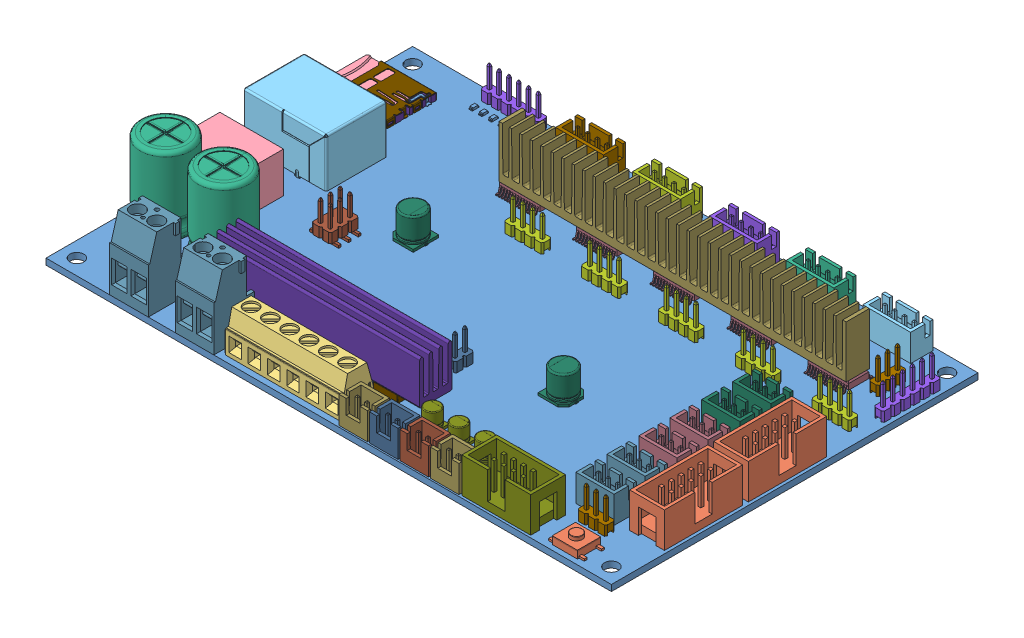
SolidWorks assembly MKS SBase V1.3, configuration Default. Lengths in mm.
Overall size (148.75 24.1 95).
76 component instances, 39 part files, 151 mates.
Components (placement in the parent):
- MKS SBase PCB-1: MKS SBase PCB [Default] at origin size (146.5 1.6 95)
- 10 pin male socket -2: 10 pin male socket  [Default] at (92.5901 0 -6.7406) x (0 0 -1) z (1 0 0) size (20.25 12.5 9)
- 10 pin male socket -3: 10 pin male socket  [Default] at (92.5901 0 -28.4906) x (0 0 -1) z (1 0 0) size (20.25 12.5 9)
- 6 pin terminal block-1: 6 pin terminal block [Default] at (-13.25 0 37.7021) size (30.6 13.8 8.3)
- USB socket-1: USB socket [Default] at (-15.2875 4.6912 16.0684) size (16.5 14.22 14.86)
- JST XH 4 Purple-1: JST XH 4 Purple [Default] at (56.25 0 -43.725) x (-1 0 0) z (0 0 -1) size (12.4 10.45 5.75)
- JST XH 4 Black-1: JST XH 4 Black [Default] at (36.35 0 -43.725) x (-1 0 0) z (0 0 -1) size (12.4 10.45 5.75)
- JST XH 4 Blue-1: JST XH 4 Blue [Default] at (-3.45 0 -43.725) x (-1 0 0) z (0 0 -1) size (12.4 10.45 5.75)
- JST XH 4 Green-1: JST XH 4 Green [Default] at (16.45 0 -43.725) x (-1 0 0) z (0 0 -1) size (12.4 10.45 5.75)
- JST XH 4 Red-1: JST XH 4 Red [Default] at (-23.35 0 -43.725) x (-1 0 0) z (0 0 -1) size (12.4 10.45 5.75)
- JST XH 2 Black-1: JST XH 2 Black [Default] at (13.85 0 44.225) size (7.4 10.45 5.75)
- JST XH 2 Purple-1: JST XH 2 Purple [Default] at (21.75 0 44.225) size (7.4 10.45 5.75)
- JST XH 2 White-1: JST XH 2 White [Default] at (5.95 0 44.225) size (7.4 10.45 5.75)
- JST XH 3 Blue-1: JST XH 3 Blue [Default] at (55.4 0 14.725) x (-1 0 0) z (0 0 -1) size (9.9 10.45 5.75)
- JST XH 3 Green-1: JST XH 3 Green [Default] at (55.4 0 31.025) x (-1 0 0) z (0 0 -1) size (9.9 10.45 5.75)
- JST XH 3 Red-1: JST XH 3 Red [Default] at (55.4 0 -1.575) x (-1 0 0) z (0 0 -1) size (9.9 10.45 5.75)
- JST XH 2 White-2: JST XH 2 White [Default] at (29.65 0 44.225) size (7.4 10.45 5.75)
- 8 pin male socket -1: 8 pin male socket  [Default] at (71.2406 0 66.9901) size (17.85 12.5 9)
- JST XH 3 Blue-2: JST XH 3 Blue [Default] at (55.4 0 6.675) x (-1 0 0) z (0 0 -1) size (9.9 10.45 5.75)
- JST XH 3 Green-2: JST XH 3 Green [Default] at (55.4 0 22.975) x (-1 0 0) z (0 0 -1) size (9.9 10.45 5.75)
- JST XH 3 Red-2: JST XH 3 Red [Default] at (55.4 0 -9.625) x (-1 0 0) z (0 0 -1) size (9.9 10.45 5.75)
- microSD_Connector-1: microSD_Connector [Default] at (-65.65 0 -31.475) x (0 0 -1) z (1 0 0) size (14.1 2.14 15.45)
  - microSD_Body-1: microSD_Body [Default] at origin size (14.1 1.85 15.2)
  - microSD_Cover-1: microSD_Cover [Default] at (0 1.7 0) x (1 0 0) z (0 0 -1) size (13.95 1.9 15.2)
  - microSD_Card_Detect-1: microSD_Card_Detect [Default] at (4.99 -0.05 7.4) size (4.45 1.9 2.05)
  - microSD_Spring-2: microSD_Spring [Default] at (-3.85 1.125 6.9) x (-0.521999 -0.852946 0) z (0.852946 -0.521999 0) size (1.41 10.35 1.43)
  - microSD_Pin-1: microSD_Pin [11.15] at (5.725 -0.05 -2) x (0 0 1) z (-1 0 0) size (7.35 1.15 0.6)
  - microSD_Pin-2: microSD_Pin [11.15] at (4.625 -0.05 -2) x (0 0 1) z (-1 0 0) size (7.35 1.15 0.6)
  - microSD_Pin-3: microSD_Pin [11.35] at (3.525 -0.05 -2) x (0 0 1) z (-1 0 0) size (7.35 1.15 0.6)
  - microSD_Pin-4: microSD_Pin [11.15] at (2.425 -0.05 -2) x (0 0 1) z (-1 0 0) size (7.35 1.15 0.6)
  - microSD_Pin-5: microSD_Pin [11.35] at (1.325 -0.05 -2) x (0 0 1) z (-1 0 0) size (7.35 1.15 0.6)
  - microSD_Pin-6: microSD_Pin [11.15] at (0.225 -0.05 -2) x (0 0 1) z (-1 0 0) size (7.35 1.15 0.6)
  - microSD_Pin-7: microSD_Pin [10.75] at (-0.875 -0.05 -2) x (0 0 1) z (-1 0 0) size (7.25 1.15 0.6)
  - microSD_Pin-8: microSD_Pin [11.15] at (-1.975 -0.05 -2) x (0 0 1) z (-1 0 0) size (7.35 1.15 0.6)
- Micro SD Card-1: Micro SD Card [Default] at (-68 1.05 -33.35) x (0 0 1) z (-1 0 0) size (11 0.83 15)
- RJ45_10P_TJ3009-1: RJ45_10P_TJ3009 [Default] at (-61.925 0.35 -11.1) x (0 0 1) z (-1 0 0) size (16 15.87 21.5)
- Condensator-1: Condensator [Default] at (-65.75 0.15 24) x (-1 0 0) z (0 0 -1) size (13.15 23 13.15)
- Condensator-2: Condensator [Default] at (-50.75 0.15 24) x (-1 0 0) z (0 0 -1) size (13.15 23 13.15)
- 2.54 pins 4 x 1-1: 2.54 pins 4 x 1 [Default] at (-14.68 0 -18.75) x (1 0 0) z (0 0 -1) size (10.06 11 2.5)
- 2.54 pins 4 x 1-5: 2.54 pins 4 x 1 [Default] at (25.12 0 -18.75) x (1 0 0) z (0 0 -1) size (10.06 11 2.5)
- 2.54 pins 4 x 1-6: 2.54 pins 4 x 1 [Default] at (45.02 0 -18.75) x (1 0 0) z (0 0 -1) size (10.06 11 2.5)
- 2.54 pins 4 x 1-7: 2.54 pins 4 x 1 [Default] at (64.92 0 -18.75) x (1 0 0) z (0 0 -1) size (10.06 11 2.5)
- 2.54 pins 4 x 1-8: 2.54 pins 4 x 1 [Default] at (5.22 0 -18.75) x (1 0 0) z (0 0 -1) size (10.06 11 2.5)
- 2.54 pins 6 x 1-1: 2.54 pins 6 x 1 [Default] at (71 0 -37.8175) x (0 0 1) z (-1 0 0) size (15.09 11 2.5)
- 2.54 pins 6 x 1-3: 2.54 pins 6 x 1 [Default] at (-51.2675 0 -45.4) size (15.09 11 2.5)
- 2.54 pins 3 x 1-3: 2.54 pins 3 x 1 [Default] at (55.6125 0 36.35) size (7.47 11 2.5)
- 2.54 pins 3 x 1-4: 2.54 pins 3 x 1 [Default] at (64.6 0 -30.2125) x (0 0 -1) z (1 0 0) size (7.47 11 2.5)
- 2.54 pins 2 x 1-1: 2.54 pins 2 x 1 [Default] at (4.5 0 19.2475) x (0 0 -1) z (1 0 0) size (4.93 11 2.5)
- 2.54 pins 3 x 2-3: 2.54 pins 3 x 2 [Default] at (-42.5 0.64 7.0875) x (0 0 -1) z (1 0 0) size (7.47 8.64 7.5)
- Stepper driver heatsink-1: Stepper driver heatsink [Default] at (15.75 9.25 -28.85) x (0 0 -1) z (1 0 0) size (6 13.5 90)
- Stepper driver-1: Stepper driver [Default] at (55.75 1.35 -28.85) x (0 0 -1) z (1 0 0) size (8 2.5 10.5)
- Stepper driver-2: Stepper driver [Default] at (35.75 1.35 -28.85) x (0 0 -1) z (1 0 0) size (8 2.5 10.5)
- Stepper driver-3: Stepper driver [Default] at (15.75 1.35 -28.85) x (0 0 -1) z (1 0 0) size (8 2.5 10.5)
- Stepper driver-4: Stepper driver [Default] at (-4.25 1.35 -28.85) x (0 0 -1) z (1 0 0) size (8 2.5 10.5)
- Stepper driver-5: Stepper driver [Default] at (-24.25 1.35 -28.85) x (0 0 -1) z (1 0 0) size (8 2.5 10.5)
- Power terminal block-1: Power terminal block [Default] at (-51.75 0 42.25) x (-1 0 0) z (0 0 -1) size (10.55 20.8 10.5)
- Power terminal block-2: Power terminal block [Default] at (-34.75 0 42.25) x (-1 0 0) z (0 0 -1) size (10.55 20.8 10.5)
- Elco100_35-5: Elco100_35 [Default] at (-30.25 0.64 -4.65) x (0 0 1) z (-1 0 0) size (6.6 6.95 7)
- Elco100_35-6: Elco100_35 [Default] at (24.65 0.64 11.3) x (0 0 -1) z (1 0 0) size (6.6 6.95 7)
- Elco100_35-7: Elco100_35 [Default] at (-32.05 0.64 -36) x (0 0 -1) z (1 0 0) size (6.6 6.95 7)
- Elco100_35-8: Elco100_35 [Default] at (-12.05 0.64 -36) x (0 0 -1) z (1 0 0) size (6.6 6.95 7)
- Elco100_35-9: Elco100_35 [Default] at (7.95 0.64 -36) x (0 0 -1) z (1 0 0) size (6.6 6.95 7)
- Elco100_35-10: Elco100_35 [Default] at (27.95 0.64 -36) x (0 0 -1) z (1 0 0) size (6.6 6.95 7)
- Elco100_35-11: Elco100_35 [Default] at (47.95 0.64 -36) x (0 0 -1) z (1 0 0) size (6.6 6.95 7)
- Elco10_35-1: Elco10_35 [Default] at (35.2 0.64 35.25) size (4.3 4.65 4.6)
- Elco10_35-2: Elco10_35 [Default] at (28.35 0.64 35.25) size (4.3 4.65 4.6)
- Elco10_35-3: Elco10_35 [Default] at (21.5 0.64 35.25) size (4.3 4.65 4.6)
- Elco10_35-4: Elco10_35 [Default] at (14.65 0.64 35.25) size (4.3 4.65 4.6)
- Power FAT heatsink-1: Power FAT heatsink [Default] at (-16.55 2 30.7) size (55 11.25 8.49)
- Power FAT-1: Power FAT [Default] at (-34.925 0 30.7) x (-1 0 0) z (0 0 -1) size (6.35 2 11)
- Power FAT-2: Power FAT [Default] at (-22.675 0 30.7) x (-1 0 0) z (0 0 -1) size (6.35 2 11)
- Power FAT-3: Power FAT [Default] at (-10.425 0 30.7) x (-1 0 0) z (0 0 -1) size (6.35 2 11)
- Power FAT-4: Power FAT [Default] at (1.825 0 30.7) x (-1 0 0) z (0 0 -1) size (6.35 2 11)
- Series of LEDs-1: Series of LEDs [Default] at (-46.425 0 -41.575) size (10.85 0.6 1.75)
- Reset button-1: Reset button [Default] at (59.9 0 43.2) size (9.25 2.95 6.02)
- 4 LEDs power outputs-1: 4 LEDs power outputs [Default] at (-12.2 0 25.075) size (37.6 0.6 1.75)
Mates (geometry in assembly coordinates):
- Coincident3: coincident aligned: plane of MKS SBase PCB-1 through (0 0 0) normal (1 0 0); plane of assembly through (0 0 0) normal (1 0 0)
- Coincident8: coincident aligned: plane of 10 pin male socket -2 through (72.5 9.1 33) normal (1 0 0); plane of 10 pin male socket -3 through (72.5 9.1 11.25) normal (1 0 0)
- Distance3: distance = 14.5 mm aligned: plane of 10 pin male socket -2 through (63.5 9.1 33) normal (0 0 1); plane of MKS SBase PCB-1 through (-73.25 -1.6 47.5) normal (0 0 1)
- Distance4: distance = 42 mm anti-aligned: plane of 10 pin male socket -2 through (63.5 9.1 33) normal (0 0 1); plane of 10 pin male socket -3 through (63.5 9.1 -9) normal (0 0 -1)
- Distance5: distance = 0.75 mm aligned: plane of 10 pin male socket -2 through (72.5 9.1 33) normal (1 0 0); plane of MKS SBase PCB-1 through (73.25 -1.6 -47.5) normal (1 0 0)
- Coincident15: coincident anti-aligned: plane of MKS SBase PCB-1 through (0 0 0) normal (0 1 0); plane of 6 pin terminal block-1 through (1.75 0 46) normal (0 -1 0)
- Distance6: distance = 71.5 mm aligned: plane of 6 pin terminal block-1 through (1.75 7.1842 38.5787) normal (1 0 0); plane of MKS SBase PCB-1 through (73.25 -1.6 -47.5) normal (1 0 0)
- Distance7: distance = 1.5 mm aligned: plane of 6 pin terminal block-1 through (1.75 5.6981 46) normal (0 0 1); plane of MKS SBase PCB-1 through (-73.25 -1.6 47.5) normal (0 0 1)
- Coincident18: coincident anti-aligned: plane of MKS SBase PCB-1 through (0 0 0) normal (0 1 0); plane of USB socket-1 through (-72.95 0 2.75) normal (0 -1 0)
- Distance8: distance = 44.75 mm anti-aligned: plane of USB socket-1 through (-72.95 10.5 2.75) normal (0 0 -1); plane of MKS SBase PCB-1 through (-73.25 -1.6 47.5) normal (0 0 1)
- Distance9: distance = 0.3 mm aligned: plane of USB socket-1 through (-72.95 0 2.75) normal (-1 0 0); plane of MKS SBase PCB-1 through (-73.25 -1.6 -47.5) normal (-1 0 0)
- Coincident21: coincident aligned: plane of JST XH 4 Black-1 through (36.35 0 -43.725) normal (0 -1 0); plane of JST XH 4 Blue-1 through (-3.45 0 -43.725) normal (0 -1 0)
- Coincident22: coincident aligned: plane of JST XH 4 Purple-1 through (56.25 0 -43.725) normal (0 -1 0); plane of JST XH 4 Blue-1 through (-3.45 0 -43.725) normal (0 -1 0)
- Coincident26: coincident aligned: plane of JST XH 4 Black-1 through (42.55 7 -40.85) normal (0 0 1); plane of JST XH 4 Blue-1 through (2.75 7 -40.85) normal (0 0 1)
- Coincident27: coincident aligned: plane of JST XH 4 Blue-1 through (2.75 7 -40.85) normal (0 0 1); plane of JST XH 4 Green-1 through (22.65 7 -40.85) normal (0 0 1)
- Distance15: distance = 0.9 mm aligned: plane of MKS SBase PCB-1 through (-73.25 -1.6 -47.5) normal (0 0 -1); plane of JST XH 4 Red-1 through (-17.15 7 -46.6) normal (0 0 -1)
- Coincident37: coincident anti-aligned: plane of MKS SBase PCB-1 through (0 0 0) normal (0 1 0); plane of JST XH 4 Red-1 through (-23.35 0 -43.725) normal (0 -1 0)
- Distance16: distance = 43.7 mm aligned: plane of MKS SBase PCB-1 through (-73.25 -1.6 -47.5) normal (-1 0 0); plane of JST XH 4 Red-1 through (-29.55 7 -40.85) normal (-1 0 0)
- Coincident39: coincident aligned: plane of JST XH 4 Blue-1 through (2.75 7 -40.85) normal (0 0 1); plane of JST XH 4 Red-1 through (-17.15 7 -40.85) normal (0 0 1)
- Coincident40: coincident anti-aligned: plane of MKS SBase PCB-1 through (0 0 0) normal (0 1 0); plane of JST XH 4 Blue-1 through (-3.45 0 -43.725) normal (0 -1 0)
- Distance17: distance = 7.5 mm anti-aligned: plane of JST XH 4 Blue-1 through (-9.65 7 -40.85) normal (-1 0 0); plane of JST XH 4 Red-1 through (-17.15 7 -40.85) normal (1 0 0)
- Distance18: distance = 7.5 mm anti-aligned: plane of JST XH 4 Green-1 through (10.25 7 -40.85) normal (-1 0 0); plane of JST XH 4 Blue-1 through (2.75 7 -40.85) normal (1 0 0)
- Distance19: distance = 7.5 mm anti-aligned: plane of JST XH 4 Black-1 through (30.15 7 -40.85) normal (-1 0 0); plane of JST XH 4 Green-1 through (22.65 7 -40.85) normal (1 0 0)
- Coincident44: coincident aligned: plane of JST XH 4 Purple-1 through (62.45 7 -46.6) normal (0 0 -1); plane of JST XH 4 Black-1 through (42.55 7 -46.6) normal (0 0 -1)
- Distance20: distance = 7.5 mm anti-aligned: plane of JST XH 4 Purple-1 through (50.05 7 -40.85) normal (-1 0 0); plane of JST XH 4 Black-1 through (42.55 7 -40.85) normal (1 0 0)
- Coincident47: coincident aligned: plane of JST XH 2 Purple-1 through (18.05 7 47.1) normal (0 0 1); plane of JST XH 2 White-2 through (25.95 7 47.1) normal (0 0 1)
- Coincident48: coincident aligned: plane of JST XH 2 Black-1 through (10.15 7 47.1) normal (0 0 1); plane of JST XH 2 Purple-1 through (18.05 7 47.1) normal (0 0 1)
- Coincident49: coincident aligned: plane of JST XH 2 Black-1 through (10.15 7 47.1) normal (0 0 1); plane of JST XH 2 White-1 through (2.25 7 47.1) normal (0 0 1)
- Coincident50: coincident aligned: plane of JST XH 2 Black-1 through (13.85 0 44.225) normal (0 -1 0); plane of JST XH 2 White-2 through (29.65 0 44.225) normal (0 -1 0)
- Coincident51: coincident aligned: plane of JST XH 2 Purple-1 through (21.75 0 44.225) normal (0 -1 0); plane of JST XH 2 White-2 through (29.65 0 44.225) normal (0 -1 0)
- Coincident52: coincident aligned: plane of JST XH 2 Purple-1 through (21.75 0 44.225) normal (0 -1 0); plane of JST XH 2 White-1 through (5.95 0 44.225) normal (0 -1 0)
- Coincident53: coincident anti-aligned: plane of MKS SBase PCB-1 through (0 0 0) normal (0 1 0); plane of JST XH 2 Black-1 through (13.85 0 44.225) normal (0 -1 0)
- Coincident54: coincident anti-aligned: plane of MKS SBase PCB-1 through (0 0 0) normal (0 1 0); plane of 8 pin male socket -1 through (71.2406 0 66.9901) normal (0 -1 0)
- Distance21: distance = 21.5 mm aligned: plane of 8 pin male socket -1 through (51.75 9.1 37.9) normal (1 0 0); plane of MKS SBase PCB-1 through (73.25 -1.6 -47.5) normal (1 0 0)
- Distance22: distance = 0.6 mm aligned: plane of 8 pin male socket -1 through (33.9 9.1 46.9) normal (0 0 1); plane of MKS SBase PCB-1 through (-73.25 -1.6 47.5) normal (0 0 1)
- Distance23: distance = 0.4 mm aligned: plane of JST XH 2 White-1 through (2.25 7 47.1) normal (0 0 1); plane of MKS SBase PCB-1 through (-73.25 -1.6 47.5) normal (0 0 1)
- Distance24: distance = 0.5 mm anti-aligned: plane of 6 pin terminal block-1 through (1.75 7.1842 38.5787) normal (1 0 0); plane of JST XH 2 White-1 through (2.25 7 41.35) normal (-1 0 0)
- Distance25: distance = 0.5 mm anti-aligned: plane of JST XH 2 White-1 through (9.65 7 41.35) normal (1 0 0); plane of JST XH 2 Black-1 through (10.15 7 41.35) normal (-1 0 0)
- Distance26: distance = 0.5 mm anti-aligned: plane of JST XH 2 Black-1 through (17.55 7 41.35) normal (1 0 0); plane of JST XH 2 Purple-1 through (18.05 7 41.35) normal (-1 0 0)
- Distance27: distance = 0.5 mm anti-aligned: plane of JST XH 2 White-2 through (25.95 7 41.35) normal (-1 0 0); plane of JST XH 2 Purple-1 through (25.45 7 41.35) normal (1 0 0)
- Distance28: distance = 12.9 mm aligned: plane of JST XH 3 Red-2 through (60.35 7 -6.75) normal (1 0 0); plane of MKS SBase PCB-1 through (73.25 -1.6 -47.5) normal (1 0 0)
- Coincident64: coincident anti-aligned: plane of MKS SBase PCB-1 through (0 0 0) normal (0 1 0); plane of JST XH 3 Red-2 through (55.4 0 -9.625) normal (0 -1 0)
- Coincident65: coincident aligned: plane of JST XH 3 Red-1 through (50.45 7 1.3) normal (-1 0 0); plane of JST XH 3 Red-2 through (50.45 7 -6.75) normal (-1 0 0)
- Coincident66: coincident aligned: plane of JST XH 3 Red-1 through (55.4 0 -1.575) normal (0 -1 0); plane of JST XH 3 Red-2 through (55.4 0 -9.625) normal (0 -1 0)
- Coincident67: coincident aligned: plane of JST XH 3 Red-1 through (50.45 7 1.3) normal (-1 0 0); plane of JST XH 3 Blue-2 through (50.45 7 9.55) normal (-1 0 0)
- Coincident68: coincident aligned: plane of JST XH 3 Blue-2 through (55.4 0 6.675) normal (0 -1 0); plane of JST XH 3 Red-2 through (55.4 0 -9.625) normal (0 -1 0)
- Coincident69: coincident aligned: plane of JST XH 3 Blue-1 through (50.45 7 17.6) normal (-1 0 0); plane of JST XH 3 Blue-2 through (50.45 7 9.55) normal (-1 0 0)
- Coincident70: coincident aligned: plane of JST XH 3 Blue-1 through (55.4 0 14.725) normal (0 -1 0); plane of JST XH 3 Red-2 through (55.4 0 -9.625) normal (0 -1 0)
- Coincident71: coincident aligned: plane of JST XH 3 Blue-1 through (50.45 7 17.6) normal (-1 0 0); plane of JST XH 3 Green-2 through (50.45 7 25.85) normal (-1 0 0)
- Coincident72: coincident aligned: plane of JST XH 3 Green-2 through (55.4 0 22.975) normal (0 -1 0); plane of JST XH 3 Red-2 through (55.4 0 -9.625) normal (0 -1 0)
- Coincident73: coincident aligned: plane of JST XH 3 Green-1 through (50.45 7 33.9) normal (-1 0 0); plane of JST XH 3 Green-2 through (50.45 7 25.85) normal (-1 0 0)
- Coincident74: coincident aligned: plane of JST XH 3 Green-1 through (55.4 0 31.025) normal (0 -1 0); plane of JST XH 3 Red-2 through (55.4 0 -9.625) normal (0 -1 0)
- Distance29: distance = 60 mm anti-aligned: plane of JST XH 3 Red-2 through (60.35 7 -12.5) normal (0 0 -1); plane of MKS SBase PCB-1 through (-73.25 -1.6 47.5) normal (0 0 1)
- Distance31: distance = 2.3 mm anti-aligned: plane of JST XH 3 Green-1 through (60.35 7 28.15) normal (0 0 -1); plane of JST XH 3 Green-2 through (60.35 7 25.85) normal (0 0 1)
- Distance32: distance = 2.5 mm anti-aligned: plane of JST XH 3 Blue-1 through (60.35 7 17.6) normal (0 0 1); plane of JST XH 3 Green-2 through (60.35 7 20.1) normal (0 0 -1)
- Distance33: distance = 2.3 mm anti-aligned: plane of JST XH 3 Blue-2 through (60.35 7 9.55) normal (0 0 1); plane of JST XH 3 Blue-1 through (60.35 7 11.85) normal (0 0 -1)
- Distance34: distance = 2.5 mm anti-aligned: plane of JST XH 3 Blue-2 through (60.35 7 3.8) normal (0 0 -1); plane of JST XH 3 Red-1 through (60.35 7 1.3) normal (0 0 1)
- Distance35: distance = 2.3 mm anti-aligned: plane of JST XH 3 Red-2 through (60.35 7 -6.75) normal (0 0 1); plane of JST XH 3 Red-1 through (60.35 7 -4.45) normal (0 0 -1)
- Coincident85: coincident aligned: plane of MKS SBase PCB-1 through (-73.25 -1.6 -47.5) normal (-1 0 0); plane of microSD_Connector-1/microSD_Body-1 through (-73.25 1.7 -24.65) normal (-1 0 0)
- Coincident86: coincident anti-aligned: plane of MKS SBase PCB-1 through (0 0 0) normal (0 1 0); plane of microSD_Connector-1/microSD_Body-1 through (-65.65 0 -31.475) normal (0 -1 0)
- Distance37: distance = 9.05 mm aligned: plane of microSD_Connector-1/microSD_Cover-1 through (-65.65 1.7 -38.45) normal (0 0 -1); plane of MKS SBase PCB-1 through (-73.25 -1.6 -47.5) normal (0 0 -1)
- Coincident92: coincident aligned: plane of microSD_Connector-1/microSD_Cover-1 through (-65.65 1.85 -31.475) normal (0 1 0); plane of Micro SD Card-1 through (-74.9 1.85 -37.5) normal (0 1 0)
- Parallel2: parallel anti-aligned: plane of microSD_Connector-1/microSD_Cover-1 through (-65.65 1.7 -38.3) normal (0 0 1); plane of Micro SD Card-1 through (-74.9 1.55 -38.1) normal (0 0 -1)
- Distance39: distance = 0.3 mm aligned: plane of Micro SD Card-1 through (-64.3 1.025 -37.65) normal (0 0 -1); plane of microSD_Connector-1/microSD_Pin-1 through (-68.4517 0.1 -37.35) normal (0 0 -1)
- Distance41: distance = 2.25 mm aligned: plane of microSD_Connector-1/microSD_Body-1 through (-73.25 1.7 -24.65) normal (-1 0 0); plane of Micro SD Card-1 through (-75.5 1.55 -27.7) normal (-1 0 0)
- Coincident94: coincident anti-aligned: plane of MKS SBase PCB-1 through (0 0 0) normal (0 1 0); plane of RJ45_10P_TJ3009-1 through (-61.925 0 -11.1) normal (0 -1 0)
- Distance43: distance = 0.4 mm aligned: plane of RJ45_10P_TJ3009-1 through (-72.85 13.02 -11.1) normal (-1 0 0); plane of MKS SBase PCB-1 through (-73.25 -1.6 -47.5) normal (-1 0 0)
- Distance44: distance = 28.5 mm aligned: plane of RJ45_10P_TJ3009-1 through (-61.925 13.02 -19) normal (0 0 -1); plane of MKS SBase PCB-1 through (-73.25 -1.6 -47.5) normal (0 0 -1)
- Coincident95: coincident aligned: plane of Condensator-1 through (-65.75 0.15 24) normal (0 0 -1); plane of Condensator-2 through (-50.75 0.15 24) normal (0 0 -1)
- Distance45: distance = 7.5 mm aligned: plane of Condensator-1 through (-65.75 0.15 24) normal (-1 0 0); plane of MKS SBase PCB-1 through (-73.25 -1.6 -47.5) normal (-1 0 0)
- Coincident97: coincident aligned: plane of Condensator-1 through (-65.75 0.15 24) normal (0 -1 0); plane of Condensator-2 through (-50.75 0.15 24) normal (0 -1 0)
- Coincident98: coincident anti-aligned: plane of MKS SBase PCB-1 through (0 0 0) normal (0 1 0); plane of Condensator-1 through (-65.75 0 24) normal (0 -1 0)
- Distance46: distance = 15 mm aligned: plane of Condensator-1 through (-65.75 0.15 24) normal (-1 0 0); plane of Condensator-2 through (-50.75 0.15 24) normal (-1 0 0)
- Distance47: distance = 23.5 mm anti-aligned: plane of Condensator-2 through (-50.75 0.15 24) normal (0 0 -1); plane of MKS SBase PCB-1 through (-73.25 -1.6 47.5) normal (0 0 1)
- Coincident101: coincident anti-aligned: plane of MKS SBase PCB-1 through (0 0 0) normal (0 1 0); plane of 2.54 pins 4 x 1-1 through (-14.68 0 -18.75) normal (0 -1 0)
- Distance48: distance = 30 mm anti-aligned: plane of 2.54 pins 4 x 1-1 through (-17.715 2.54 -17.5) normal (0 0 1); plane of MKS SBase PCB-1 through (-73.25 -1.6 -47.5) normal (0 0 -1)
- Coincident104: coincident anti-aligned: plane of JST XH 4 Blue-1 through (-9.65 7 -40.85) normal (-1 0 0); plane of 2.54 pins 4 x 1-1 through (-9.65 2.54 -19.5) normal (1 0 0)
- Coincident108: coincident aligned: plane of 2.54 pins 4 x 1-5 through (25.12 0 -18.75) normal (0 -1 0); plane of 2.54 pins 4 x 1-8 through (5.22 0 -18.75) normal (0 -1 0)
- Coincident109: coincident aligned: plane of 2.54 pins 4 x 1-5 through (25.12 0 -18.75) normal (0 -1 0); plane of 2.54 pins 4 x 1-6 through (45.02 0 -18.75) normal (0 -1 0)
- Coincident110: coincident aligned: plane of 2.54 pins 4 x 1-6 through (45.02 0 -18.75) normal (0 -1 0); plane of 2.54 pins 4 x 1-7 through (64.92 0 -18.75) normal (0 -1 0)
- Coincident111: coincident anti-aligned: plane of MKS SBase PCB-1 through (0 0 0) normal (0 1 0); plane of 2.54 pins 4 x 1-8 through (5.22 0 -18.75) normal (0 -1 0)
- Coincident112: coincident aligned: plane of 2.54 pins 4 x 1-1 through (-16.775 2.54 -20) normal (0 0 -1); plane of 2.54 pins 4 x 1-8 through (0.56 2.54 -20) normal (0 0 -1)
- Coincident113: coincident aligned: plane of 2.54 pins 4 x 1-5 through (20.46 2.54 -20) normal (0 0 -1); plane of 2.54 pins 4 x 1-8 through (0.56 2.54 -20) normal (0 0 -1)
- Coincident114: coincident aligned: plane of 2.54 pins 4 x 1-5 through (20.46 2.54 -20) normal (0 0 -1); plane of 2.54 pins 4 x 1-6 through (40.36 2.54 -20) normal (0 0 -1)
- Coincident115: coincident aligned: plane of 2.54 pins 4 x 1-6 through (40.36 2.54 -20) normal (0 0 -1); plane of 2.54 pins 4 x 1-7 through (62.825 2.54 -20) normal (0 0 -1)
- Coincident116: coincident anti-aligned: plane of JST XH 4 Green-1 through (10.25 7 -40.85) normal (-1 0 0); plane of 2.54 pins 4 x 1-8 through (10.25 2.54 -19.5) normal (1 0 0)
- Coincident117: coincident anti-aligned: plane of JST XH 4 Black-1 through (30.15 7 -40.85) normal (-1 0 0); plane of 2.54 pins 4 x 1-5 through (30.15 2.54 -19.5) normal (1 0 0)
- Coincident118: coincident anti-aligned: plane of JST XH 4 Purple-1 through (50.05 7 -40.85) normal (-1 0 0); plane of 2.54 pins 4 x 1-6 through (50.05 2.54 -19.5) normal (1 0 0)
- Distance49: distance = 9.84 mm anti-aligned: plane of 2.54 pins 4 x 1-6 through (50.05 2.54 -19.5) normal (1 0 0); plane of 2.54 pins 4 x 1-7 through (59.89 2.54 -18) normal (-1 0 0)
- Coincident121: coincident aligned: plane of 2.54 pins 6 x 1-1 through (71 0 -37.8175) normal (0 -1 0); plane of 2.54 pins 6 x 1-3 through (-51.2675 0 -45.4) normal (0 -1 0)
- Coincident122: coincident anti-aligned: plane of MKS SBase PCB-1 through (0 0 0) normal (0 1 0); plane of 2.54 pins 6 x 1-3 through (-51.2675 0 -45.4) normal (0 -1 0)
- Distance50: distance = 0.85 mm aligned: plane of 2.54 pins 6 x 1-3 through (-46.975 2.54 -46.65) normal (0 0 -1); plane of MKS SBase PCB-1 through (-73.25 -1.6 -47.5) normal (0 0 -1)
- Distance51: distance = 20.8 mm aligned: plane of MKS SBase PCB-1 through (-73.25 -1.6 -47.5) normal (-1 0 0); plane of 2.54 pins 6 x 1-3 through (-52.45 2.54 -46.15) normal (-1 0 0)
- Distance52: distance = 1 mm aligned: plane of 2.54 pins 6 x 1-1 through (72.25 2.54 -33.525) normal (1 0 0); plane of MKS SBase PCB-1 through (73.25 -1.6 -47.5) normal (1 0 0)
- Distance53: distance = 8.5 mm aligned: plane of 2.54 pins 6 x 1-1 through (71.75 2.54 -39) normal (0 0 -1); plane of MKS SBase PCB-1 through (-73.25 -1.6 -47.5) normal (0 0 -1)
- Coincident127: coincident aligned: plane of 2.54 pins 3 x 1-3 through (55.6125 0 36.35) normal (0 -1 0); plane of 2.54 pins 3 x 1-4 through (64.6 0 -30.2125) normal (0 -1 0)
- Coincident128: coincident anti-aligned: plane of MKS SBase PCB-1 through (0 0 0) normal (0 1 0); plane of 2.54 pins 3 x 1-3 through (55.6125 0 36.35) normal (0 -1 0)
- Distance54: distance = 11 mm aligned: plane of 2.54 pins 3 x 1-4 through (63.85 2.54 -36.5) normal (0 0 -1); plane of MKS SBase PCB-1 through (-73.25 -1.6 -47.5) normal (0 0 -1)
- Distance55: distance = 9.9 mm anti-aligned: plane of 2.54 pins 3 x 1-4 through (63.35 2.54 -31.965) normal (-1 0 0); plane of MKS SBase PCB-1 through (73.25 -1.6 -47.5) normal (1 0 0)
- Distance56: distance = 11.35 mm aligned: plane of 2.54 pins 3 x 1-3 through (61.9 2.54 35.6) normal (1 0 0); plane of MKS SBase PCB-1 through (73.25 -1.6 -47.5) normal (1 0 0)
- Distance57: distance = 9.9 mm aligned: plane of 2.54 pins 3 x 1-3 through (61.53 2.54 37.6) normal (0 0 1); plane of MKS SBase PCB-1 through (-73.25 -1.6 47.5) normal (0 0 1)
- Coincident133: coincident anti-aligned: plane of MKS SBase PCB-1 through (0 0 0) normal (0 1 0); plane of 2.54 pins 2 x 1-1 through (4.5 0 19.2475) normal (0 -1 0)
- Distance58: distance = 32 mm anti-aligned: plane of 2.54 pins 2 x 1-1 through (3.75 2.54 15.5) normal (0 0 -1); plane of MKS SBase PCB-1 through (-73.25 -1.6 47.5) normal (0 0 1)
- Distance59: distance = 1 mm aligned: plane of 2.54 pins 2 x 1-1 through (3.25 2.54 18.435) normal (-1 0 0); plane of JST XH 2 White-1 through (2.25 7 41.35) normal (-1 0 0)
- Coincident136: coincident anti-aligned: plane of MKS SBase PCB-1 through (0 0 0) normal (0 1 0); plane of 2.54 pins 3 x 2-3 through (-39.68 0 6.7675) normal (0 -1 0)
- Distance60: distance = 34.5 mm anti-aligned: plane of 2.54 pins 3 x 2-3 through (-38.75 3.18 5.335) normal (1 0 0); plane of MKS SBase PCB-1 through (-73.25 -1.6 -47.5) normal (-1 0 0)
- Distance61: distance = 46.7 mm anti-aligned: plane of 2.54 pins 3 x 2-3 through (-39.25 3.18 0.8) normal (0 0 -1); plane of MKS SBase PCB-1 through (-73.25 -1.6 47.5) normal (0 0 1)
- Distance62: distance = 15.65 mm aligned: plane of Stepper driver heatsink-1 through (15.75 9.25 -31.85) normal (0 0 -1); plane of MKS SBase PCB-1 through (-73.25 -1.6 -47.5) normal (0 0 -1)
- Distance63: distance = 12.5 mm aligned: plane of Stepper driver heatsink-1 through (60.75 16 -31.85) normal (1 0 0); plane of MKS SBase PCB-1 through (73.25 -1.6 -47.5) normal (1 0 0)
- Symmetric1: symmetric aligned: plane of Stepper driver heatsink-1 through (15.75 9.25 -28.85) normal (0 0 -1); plane of Stepper driver-1 through (61 0.2 -31.475) normal (0 0 -1); plane of Stepper driver-1 through (61 2.5 -26.225) normal (0 0 1)
- Coincident141: coincident anti-aligned: plane of Stepper driver heatsink-1 through (60.75 2.5 -31.85) normal (0 -1 0); plane of Stepper driver-1 through (61 2.5 -31.475) normal (0 1 0)
- Coincident142: coincident anti-aligned: plane of MKS SBase PCB-1 through (0 0 0) normal (0 1 0); plane of Stepper driver-1 through (60.3214 0 -24.85) normal (0 -1 0)
- Symmetric2: symmetric aligned: plane of Stepper driver heatsink-1 through (15.75 9.25 -28.85) normal (1 0 0); plane of Stepper driver-3 through (10.5 1.35 -28.85) normal (-1 0 0); plane of Stepper driver-3 through (21 1.35 -28.85) normal (1 0 0)
- Coincident143: coincident aligned: plane of Power terminal block-1 through (-56.75 0 47.5) normal (0 -1 0); plane of Power terminal block-2 through (-39.75 0 47.5) normal (0 -1 0)
- Coincident145: coincident aligned: plane of Power terminal block-1 through (-56.75 0 37) normal (0 0 -1); plane of Power terminal block-2 through (-39.75 0 37) normal (0 0 -1)
- Coincident146: coincident anti-aligned: plane of MKS SBase PCB-1 through (0 0 0) normal (0 1 0); plane of Power terminal block-1 through (-56.75 0 47.5) normal (0 -1 0)
- Coincident148: coincident aligned: plane of MKS SBase PCB-1 through (-73.25 -1.6 47.5) normal (0 0 1); plane of Power terminal block-1 through (-56.75 11.7 47.5) normal (0 0 1)
- Distance64: distance = 16.5 mm aligned: plane of Power terminal block-1 through (-56.75 0 42.25) normal (-1 0 0); plane of MKS SBase PCB-1 through (-73.25 -1.6 -47.5) normal (-1 0 0)
- Distance65: distance = 7 mm anti-aligned: plane of Power terminal block-2 through (-39.75 0 42.25) normal (-1 0 0); plane of Power terminal block-1 through (-46.75 0 42.25) normal (1 0 0)
- Coincident162: coincident aligned: plane of Elco100_35-5 through (-30.25 0 -4.65) normal (0 -1 0); plane of Elco100_35-6 through (24.65 0 11.3) normal (0 -1 0)
- Coincident163: coincident aligned: plane of Elco100_35-6 through (24.65 0 11.3) normal (0 -1 0); plane of Elco100_35-7 through (-32.05 0 -36) normal (0 -1 0)
- Coincident164: coincident anti-aligned: plane of MKS SBase PCB-1 through (0 0 0) normal (0 1 0); plane of Elco100_35-5 through (-30.25 0 -4.65) normal (0 -1 0)
- Distance69: distance = 14.8 mm anti-aligned: plane of Elco100_35-7 through (-30.1642 0 -32.7) normal (0 0 1); plane of MKS SBase PCB-1 through (-73.25 -1.6 -47.5) normal (0 0 -1)
- Distance70: distance = 18.2 mm anti-aligned: plane of Elco100_35-7 through (-35.35 0 -32.7) normal (-1 0 0); plane of JST XH 4 Red-1 through (-17.15 7 -40.85) normal (1 0 0)
- Distance71: distance = 46.3 mm anti-aligned: plane of Elco100_35-5 through (-26.95 0 -7.95) normal (1 0 0); plane of MKS SBase PCB-1 through (-73.25 -1.6 -47.5) normal (-1 0 0)
- Distance72: distance = 46.15 mm anti-aligned: plane of Elco100_35-5 through (-26.95 0 -1.35) normal (0 0 1); plane of MKS SBase PCB-1 through (-73.25 -1.6 -47.5) normal (0 0 -1)
- Distance73: distance = 51.9 mm anti-aligned: plane of Elco100_35-6 through (21.35 0 14.6) normal (-1 0 0); plane of MKS SBase PCB-1 through (73.25 -1.6 -47.5) normal (1 0 0)
- Distance74: distance = 39.5 mm anti-aligned: plane of MKS SBase PCB-1 through (-73.25 -1.6 47.5) normal (0 0 1); plane of Elco100_35-6 through (21.35 0 8) normal (0 0 -1)
- Coincident173: coincident anti-aligned: plane of MKS SBase PCB-1 through (0 0 0) normal (0 1 0); plane of Elco10_35-1 through (35.2 0 35.25) normal (0 -1 0)
- Distance75: distance = 14.4 mm anti-aligned: plane of Elco10_35-1 through (33.05 0 33.1) normal (0 0 -1); plane of MKS SBase PCB-1 through (-73.25 -1.6 47.5) normal (0 0 1)
- Distance76: distance = 40.2 mm anti-aligned: plane of Elco10_35-1 through (33.05 0 36.5515) normal (-1 0 0); plane of MKS SBase PCB-1 through (73.25 -1.6 -47.5) normal (1 0 0)
- Coincident176: coincident anti-aligned: plane of MKS SBase PCB-1 through (0 0 0) normal (0 1 0); plane of Power FAT-1 through (-34.925 0 30.7) normal (0 -1 0)
- Distance77: distance = 20.8 mm anti-aligned: plane of Power FAT-1 through (-31.75 2 26.7) normal (0 0 -1); plane of MKS SBase PCB-1 through (-73.25 -1.6 47.5) normal (0 0 1)
- Distance78: distance = 41.5 mm anti-aligned: plane of Power FAT-1 through (-31.75 2 34.7) normal (1 0 0); plane of MKS SBase PCB-1 through (-73.25 -1.6 -47.5) normal (-1 0 0)
- Symmetric4: symmetric aligned: plane of Power FAT heatsink-1 through (-16.55 2 30.7) normal (1 0 0); plane of Power FAT-1 through (-38.1 2 34.7) normal (-1 0 0); plane of Power FAT-4 through (5 2 34.7) normal (1 0 0)
- Coincident179: coincident anti-aligned: plane of Power FAT heatsink-1 through (10.95 2 34.95) normal (0 -1 0); plane of Power FAT-3 through (-10.425 2 30.7) normal (0 1 0)
- Coincident180: coincident anti-aligned: plane of Power FAT heatsink-1 through (-16.55 2 30.7) normal (0 0 1); plane of Power FAT-1 through (-34.925 0 30.7) normal (0 0 -1)
- Coincident181: coincident anti-aligned: plane of MKS SBase PCB-1 through (0 0 0) normal (0 1 0); plane of Series of LEDs-1 through (-46.425 0 -41.575) normal (0 -1 0)
- Distance79: distance = 32.25 mm anti-aligned: plane of Series of LEDs-1 through (-41 0.6 -42.2) normal (1 0 0); plane of MKS SBase PCB-1 through (-73.25 -1.6 -47.5) normal (-1 0 0)
- Distance80: distance = 6.8 mm anti-aligned: plane of Series of LEDs-1 through (-51.85 0.25 -40.7) normal (0 0 1); plane of MKS SBase PCB-1 through (-73.25 -1.6 -47.5) normal (0 0 -1)
- Coincident184: coincident anti-aligned: plane of MKS SBase PCB-1 through (0 0 0) normal (0 1 0); plane of Reset button-1 through (59.9 0 43.2) normal (0 -1 0)
- Distance81: distance = 7.3 mm anti-aligned: plane of Reset button-1 through (56.65 1.75 40.2) normal (0 0 -1); plane of MKS SBase PCB-1 through (-73.25 -1.6 47.5) normal (0 0 1)
- Distance82: distance = 16.6 mm anti-aligned: plane of Reset button-1 through (56.65 1.75 40.2) normal (-1 0 0); plane of MKS SBase PCB-1 through (73.25 -1.6 -47.5) normal (1 0 0)
- Coincident187: coincident anti-aligned: plane of MKS SBase PCB-1 through (0 0 0) normal (0 1 0); plane of 10 pin male socket -2 through (92.5901 0 -6.7406) normal (0 -1 0)
- Coincident188: coincident anti-aligned: plane of 10 pin male socket -3 through (92.5901 0 -28.4906) normal (0 -1 0); plane of MKS SBase PCB-1 through (0 0 0) normal (0 1 0)
- Coincident189: coincident anti-aligned: plane of MKS SBase PCB-1 through (0 0 0) normal (0 1 0); plane of JST XH 4 Green-1 through (16.45 0 -43.725) normal (0 -1 0)
- Coincident190: coincident aligned: plane of MKS SBase PCB-1 through (0 0 0) normal (0 0 1); plane of assembly through (0 0 0) normal (0 0 1)
- Coincident191: coincident aligned: plane of MKS SBase PCB-1 through (0 0 0) normal (0 1 0); plane of assembly through (0 0 0) normal (0 1 0)
- Coincident192: coincident anti-aligned: plane of MKS SBase PCB-1 through (0 0 0) normal (0 1 0); plane of 4 LEDs power outputs-1 through (-12.2 0 25.075) normal (0 -1 0)
- Distance83: distance = 1.25 mm anti-aligned: plane of Power FAT-3 through (-7.75 1.1 25.2265) normal (1 0 0); plane of 4 LEDs power outputs-1 through (-6.5 0.6 24.45) normal (-1 0 0)
- Distance84: distance = 0.5 mm aligned: plane of Power FAT-3 through (-8.6 0.4 23.7) normal (0 0 -1); plane of 4 LEDs power outputs-1 through (-5.65 0.25 24.2) normal (0 0 -1)
